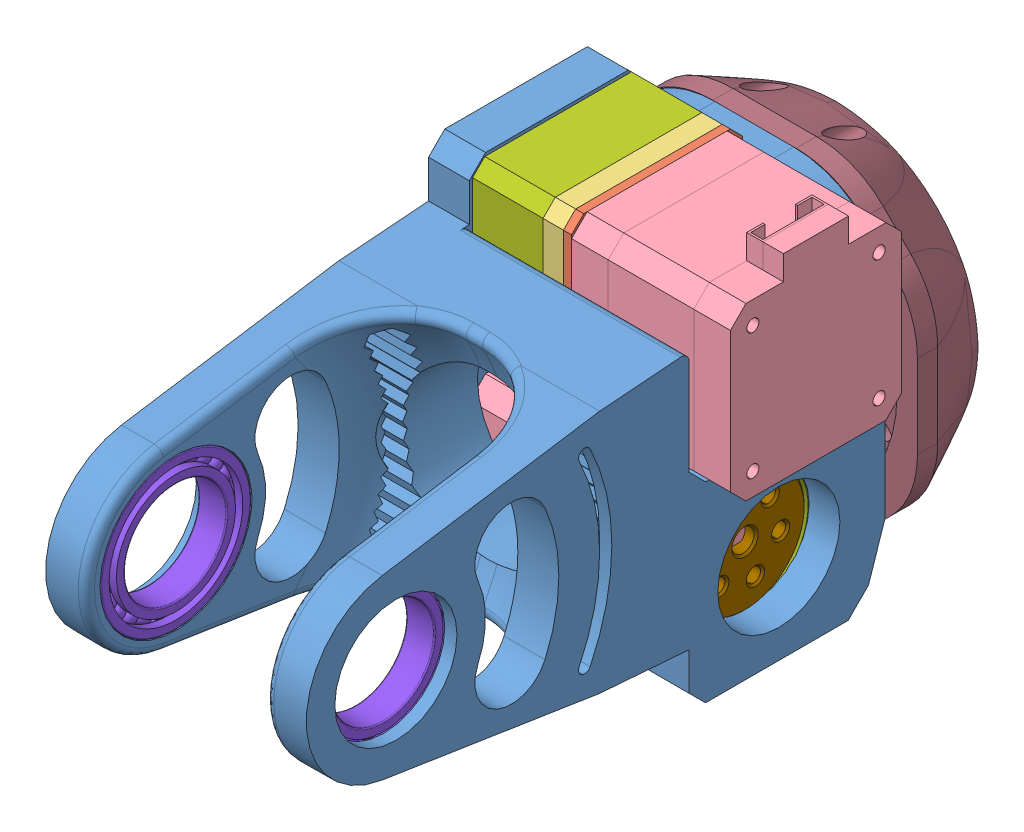
SolidWorks assembly Gelenk_3_V2, configuration Standard. Lengths in mm.
Overall size (82.38 102.22 162.01).
34 component instances, 13 part files, 8 mates.
Components (placement in the parent):
- Frame_Gelenk_3_V2-1: Frame_Gelenk_3_V2 [Standard] at origin size (64 90 142)
- Assembly_Strain_Wave_G3-1: Assembly_Strain_Wave_G3 [Standard] at (2.301 23.2382 26.189) x (0 0 1) z (-1 0 0) size (55.84 55.84 65.5)
  - Circular_Spline_G3-1: Circular_Spline_G3 [Standard] at origin size (42 42 2)
  - Circular_Spline_Teeth_G3-1: Circular_Spline_Teeth_G3 [Standard] at (0 0 2) size (42 42 5)
  - motor-1: motor [Default] at (0 0 -39) x (0 1 0) z (1 0 0) size (48 63 42)
  - Flex_Spline_G3-1: Flex_Spline_G3 [Standard] at (0 0 2) x (0.997643 0.068615 0) z (0 0 1) size (35.46 35.5 10.25)
  - Flex_Spline_Case_G3-1: Flex_Spline_Case_G3 [Standard] at (0 0 16.5) x (-0.725456 0.688269 0) z (0 0 -1) size (39.5 39.5 9.5)
  - Circular_Spline_Case_G3-1: Circular_Spline_Case_G3 [Standard] at (0 0 7) size (42 42 19.5)
  - 6805_Radial_Bearring-1: 6805_Radial_Bearring [Standard] at (0 0 16.5) x (0.860886 0.508797 0) z (-0.508797 0.860886 0) size (37 7 37)
  - Flex_Spline_Kupplung_G3-1: Flex_Spline_Kupplung_G3 [Standard] at (0 0 23.5) x (-0.958786 -0.284129 0) z (0 0 -1) size (30 30 10)
  - G3_Wave_Generator_V1-1: G3_Wave_Generator_V1 [Default] at (0 0 3.0382) x (0.997347 0.072793 0) z (0 0 1) size (24.43 33.65 11.8)
    - Wave_Generator_G3-1: Wave_Generator_G3 [Standard] at origin size (24.43 29.5 11)
    - radial ball bearing_68_din-1: radial ball bearing_68_din [DIN 625 - 623 - 8,SI,NC,8_68] at (0 10 5.2) x (0 0 -1) z (0.867763 -0.496979 0) size (4 10 10)
    - socket head thin cap screw_din-1: socket head thin cap screw_din [DIN 7984 - M3 x 8 --- 6.5N] at (0 10 9.2) x (0 0 -1) z (1 0 0) size (10 5.5 5.5)
    - socket head thin cap screw_din-2: socket head thin cap screw_din [DIN 7984 - M3 x 8 --- 6.5N] at (0 -10 9.2) x (0 0 -1) z (-1 0 0) size (10 5.5 5.5)
    - radial ball bearing_68_din-2: radial ball bearing_68_din [DIN 625 - 623 - 8,SI,NC,8_68] at (0 -10 5.2) x (0 0 -1) z (-0.867763 -0.496979 0) size (4 10 10)
- Assembly_Strain_Wave_G3-3: Assembly_Strain_Wave_G3 [Standard] at (-2.0741 -23.1375 26.7311) x (0 0 1) z (1 0 0) size (55.84 55.84 65.5)
  - Circular_Spline_G3-1: Circular_Spline_G3 [Standard] at origin size (42 42 2)
  - Circular_Spline_Teeth_G3-1: Circular_Spline_Teeth_G3 [Standard] at (0 0 2) size (42 42 5)
  - motor-1: motor [Default] at (0 0 -39) x (0 1 0) z (1 0 0) size (48 63 42)
  - Flex_Spline_G3-1: Flex_Spline_G3 [Standard] at (0 0 2) x (0.997643 0.068615 0) z (0 0 1) size (35.46 35.5 10.25)
  - Flex_Spline_Case_G3-1: Flex_Spline_Case_G3 [Standard] at (0 0 16.5) x (-0.725456 0.688269 0) z (0 0 -1) size (39.5 39.5 9.5)
  - Circular_Spline_Case_G3-1: Circular_Spline_Case_G3 [Standard] at (0 0 7) size (42 42 19.5)
  - 6805_Radial_Bearring-1: 6805_Radial_Bearring [Standard] at (0 0 16.5) x (0.860886 0.508797 0) z (-0.508797 0.860886 0) size (37 7 37)
  - Flex_Spline_Kupplung_G3-1: Flex_Spline_Kupplung_G3 [Standard] at (0 0 23.5) x (-0.958786 -0.284129 0) z (0 0 -1) size (30 30 10)
  - G3_Wave_Generator_V1-1: G3_Wave_Generator_V1 [Default] at (0 0 3.0382) x (0.997347 0.072793 0) z (0 0 1) size (24.43 33.65 11.8)
    - Wave_Generator_G3-1: Wave_Generator_G3 [Standard] at origin size (24.43 29.5 11)
    - radial ball bearing_68_din-1: radial ball bearing_68_din [DIN 625 - 623 - 8,SI,NC,8_68] at (0 10 5.2) x (0 0 -1) z (0.867763 -0.496979 0) size (4 10 10)
    - socket head thin cap screw_din-1: socket head thin cap screw_din [DIN 7984 - M3 x 8 --- 6.5N] at (0 10 9.2) x (0 0 -1) z (1 0 0) size (10 5.5 5.5)
    - socket head thin cap screw_din-2: socket head thin cap screw_din [DIN 7984 - M3 x 8 --- 6.5N] at (0 -10 9.2) x (0 0 -1) z (-1 0 0) size (10 5.5 5.5)
    - radial ball bearing_68_din-2: radial ball bearing_68_din [DIN 625 - 623 - 8,SI,NC,8_68] at (0 -10 5.2) x (0 0 -1) z (-0.867763 -0.496979 0) size (4 10 10)
- Adapter_Gelenk_3-1: Adapter_Gelenk_3 [Standard] at (0 0 -20) size (82.11 80.02 20.02)
- 6805_Radial_Bearring-1: 6805_Radial_Bearring [Standard] at (-29 0 120) x (0 1 0) z (0 0 1) size (37 7 37)
- 6805_Radial_Bearring-3: 6805_Radial_Bearring [Standard] at (22 0 120) x (0 1 0) z (0 0 1) size (37 7 37)
Mates (geometry in assembly coordinates):
- Deckungsgleich1: coincident aligned: plane of Frame_Gelenk_3_V2-1 through (0 0 0) normal (0 0 1)
- Deckungsgleich2: coincident aligned: plane of Frame_Gelenk_3_V2-1 through (0 0 0) normal (0 1 0)
- Deckungsgleich3: coincident aligned: plane of Frame_Gelenk_3_V2-1 through (0 0 0) normal (1 0 0)
- Konzentrisch1: concentric aligned: cylinder of Frame_Gelenk_3_V2-1 through (0 0 0) axis (0 0 1) radius 10; cylinder of Adapter_Gelenk_3-1 through (0 0 -20.01) axis (0 0 1) radius 25
- Deckungsgleich4: coincident anti-aligned: plane of Frame_Gelenk_3_V2-1 through (0 0 0) normal (0 0 -1); plane of Adapter_Gelenk_3-1 through (-19.0946 38.3258 0) normal (0 0 1)
- Deckungsgleich5: coincident aligned: plane of Frame_Gelenk_3_V2-1 through (40 40 5) normal (0 1 0); plane of Adapter_Gelenk_3-1 through (10.2228 40 0) normal (0 1 0)
- Deckungsgleich6: coincident anti-aligned: plane of Frame_Gelenk_3_V2-1 through (-29 0 120) normal (1 0 0); plane of 6805_Radial_Bearring-1 through (-29 0 137.3) normal (-1 0 0)
- Konzentrisch2: concentric aligned: cylinder of Frame_Gelenk_3_V2-1 through (84.7502 0 120) axis (-1 0 0) radius 18.65; cylinder of 6805_Radial_Bearring-1 through (-25.5 0 120) axis (-1 0 0) radius 18.5
